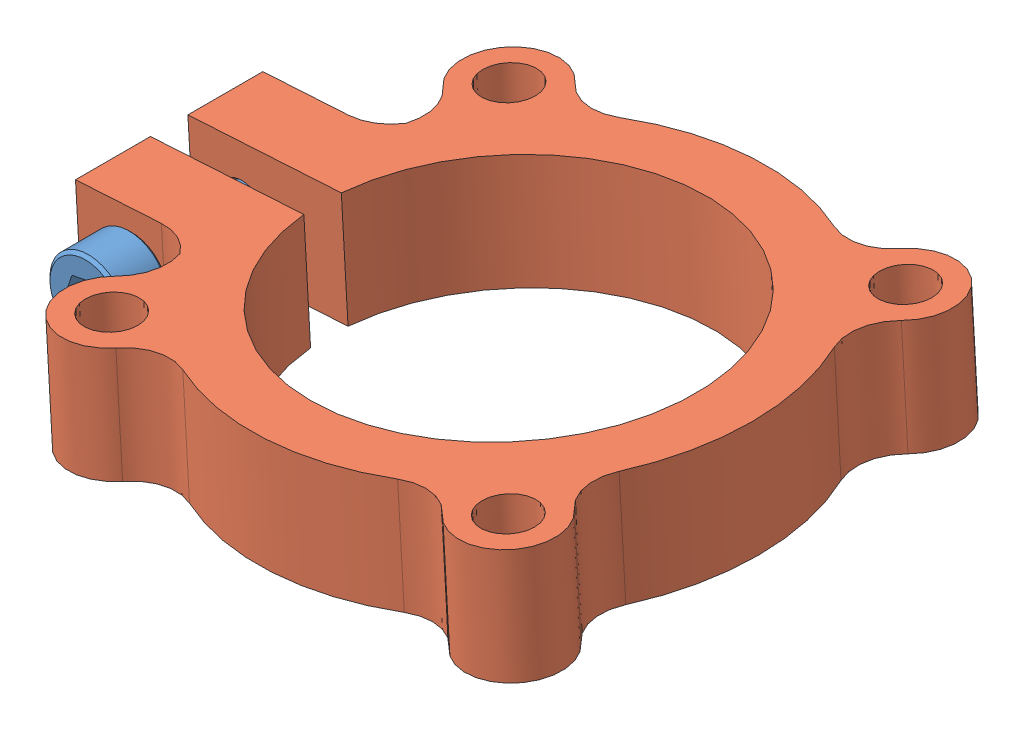
SolidWorks assembly hub_clamp_assembly, configuration Default. Lengths in mm.
Overall size (40.09 9.97 33.29).
2 component instances, 2 part files, 2 mates.
Components (placement in the parent):
- hub_clamp_set_screw-1: hub_clamp_set_screw [Default] at (3.3182 8.6936 18.55) size (5.21 5.21 16.15)
- hub_clamp-1: hub_clamp [Default] at (22.4959 13.6536 12.2) x (-0.998228 -0.059507 0) z (0 0 1) size (39.7 7.62 33.29)
Mates (geometry in assembly coordinates):
- Screw1: screw = 40: circle of assembly; cylinder of assembly; circle of hub_clamp_set_screw-1; cylinder of hub_clamp-1 through (3.3182 8.6936 18.55) axis (0 0 1) radius 1.778
- Coincident1: coincident: plane of assembly; plane of assembly; plane of hub_clamp_set_screw-1 through (3.3182 8.6936 18.55) normal (0 0 -1); plane of hub_clamp-1 through (5.2993 12.6285 18.55) normal (0 0 1)
